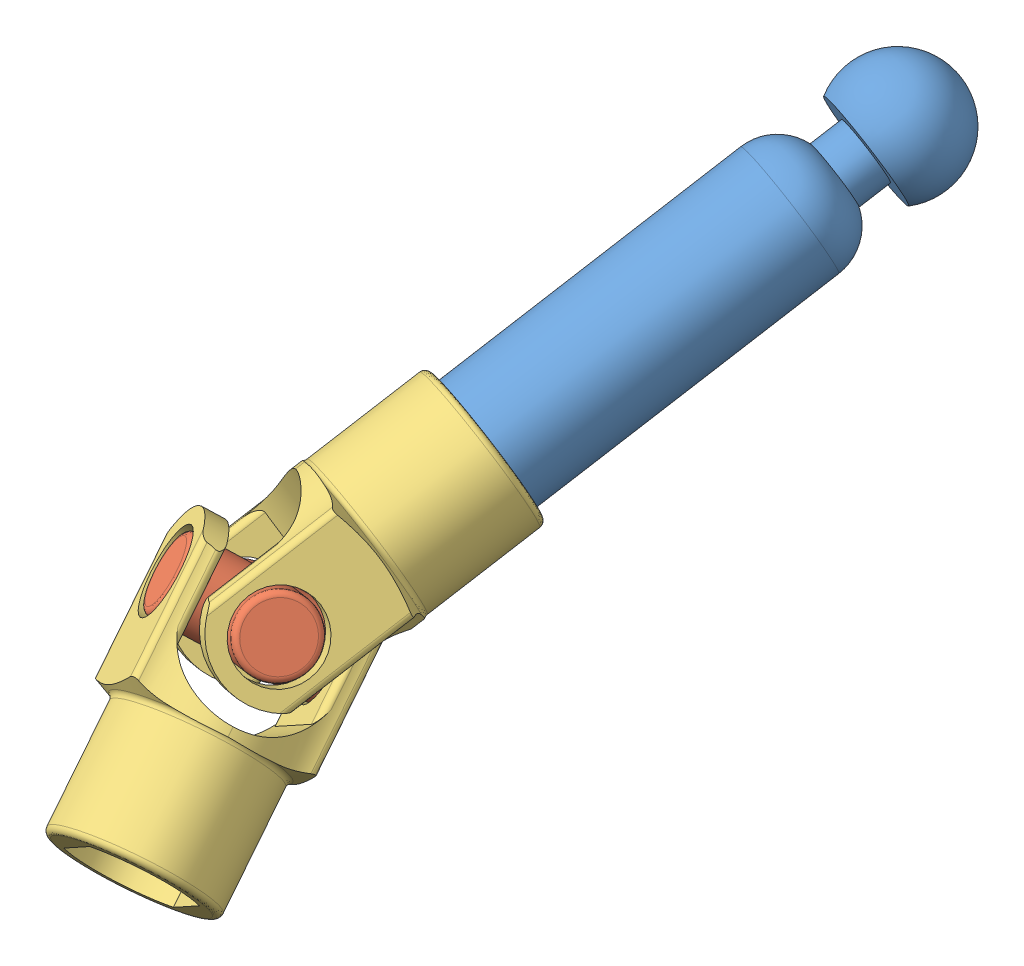
SolidWorks assembly Male Shaft Assembly LP, configuration Default. Lengths in mm.
Overall size (158.73 249.96 357.1).
4 component instances, 3 part files, 6 mates.
Components (placement in the parent):
- Male Shaft (2)-1: Male Shaft (2) [Default] at (-60.3407 42.0511 -37.1239) x (0.940425 0.057018 0.335187) z (-0.272792 -0.461903 0.843937) size (50.8 50.8 241.3)
- UJoint-1: UJoint [Default] at (-113.8585 -63.0419 176.9169) x (-0.652722 0.516118 0.554595) z (-0.757562 -0.437588 -0.484372) size (68.58 30.48 68.58)
- Yoke2-1: Yoke2 [Default] at (-124.8464 -80.0494 179.8123) x (-0.134938 0.641138 -0.75547) z (0.652722 -0.516118 -0.554595) size (114.81 68.86 68.58)
- Yoke2-2: Yoke2 [Default] at (-122.8027 -63.6967 156.1009) x (-0.272792 -0.461903 0.843937) z (-0.757562 -0.437588 -0.484372) size (114.81 68.86 68.58)
Mates (geometry in assembly coordinates):
- Concentric4: concentric anti-aligned: cylinder of UJoint-1 through (-152.8237 -85.5493 152.0033) axis (0.757562 0.437588 0.484372) radius 15.24; cylinder of Yoke2-2 through (-100.8701 -55.5395 185.2215) axis (-0.757562 -0.437588 -0.484372) radius 16.764
- Coincident6: coincident aligned: plane of UJoint-1 through (-100.8701 -55.5395 185.2215) normal (0.757562 0.437588 0.484372); plane of Yoke2-2 through (-89.1532 3.8543 113.2391) normal (0.757562 0.437588 0.484372)
- Concentric5: concentric anti-aligned: cylinder of UJoint-1 through (-104.465 -88.2421 149.5953) axis (-0.652722 0.516118 0.554595) radius 15.24; cylinder of Yoke2-1 through (-149.2287 -52.8467 187.6295) axis (0.652722 -0.516118 -0.554595) radius 16.764
- Coincident7: coincident aligned: plane of UJoint-1 through (-104.465 -88.2421 149.5953) normal (0.652722 -0.516118 -0.554595); plane of Yoke2-1 through (-75.5278 -134.1768 226.4004) normal (0.652722 -0.516118 -0.554595)
- Coincident8: coincident anti-aligned: plane of Male Shaft (2)-1 through (-115.772 -51.8076 134.3642) normal (-0.272792 -0.461903 0.843937); plane of Yoke2-2 through (-115.7825 -51.794 134.3682) normal (0.272792 0.461903 -0.843937)
- Concentric6: concentric aligned: cylinder of Male Shaft (2)-1 through (-115.772 -51.8076 134.3642) axis (0.272792 0.461903 -0.843937) radius 25.146; cylinder of Yoke2-2 through (-115.772 -51.8076 134.3642) axis (0.272792 0.461903 -0.843937) radius 25.019
